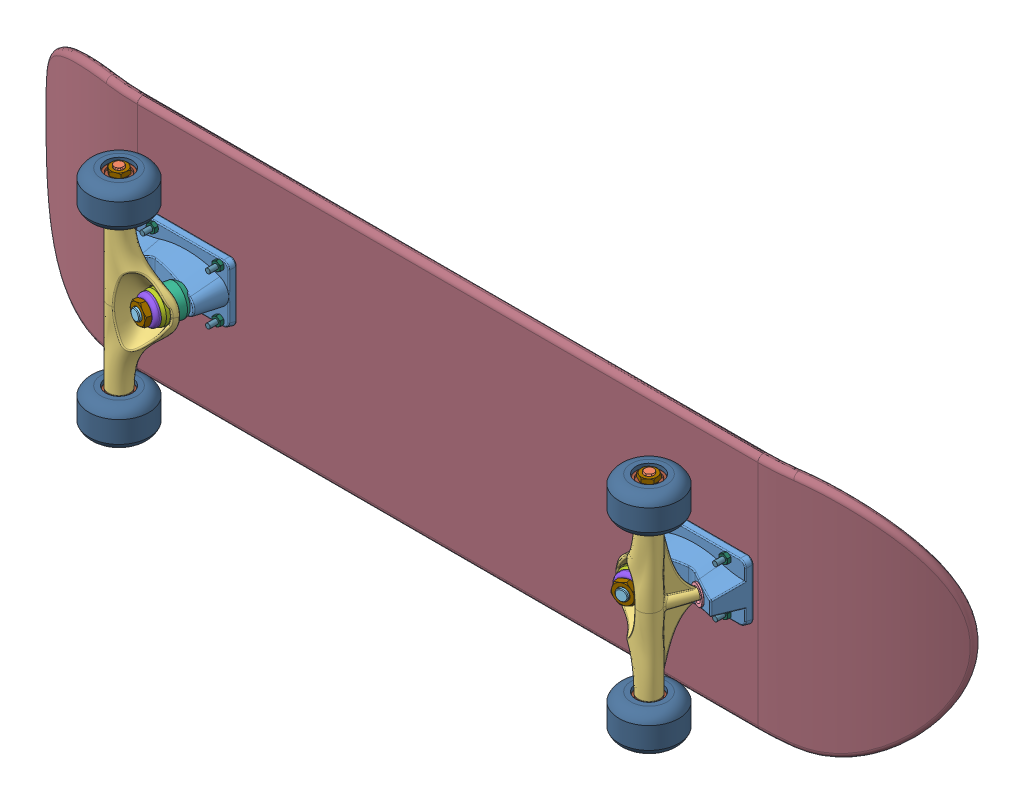
SolidWorks assembly Assembly - Skate Board, configuration Default. Lengths in mm.
Overall size (788.92 215.39 157.78).
61 component instances, 15 part files, 19 mates.
Components (placement in the parent):
- Assem1-1: Assem1 [Default] at (-144.7404 14.9244 -85.2908) x (0.992671 0 0.120847) z (-0.120847 0 0.992671) size (83.68 196.33 93.83)
  - wheels plate-1: wheels plate [Default] at (-66.8998 0 44.2716) x (0.992671 0 -0.120847) z (0.120847 0 0.992671) size (79.62 49.62 33.33)
  - axle-1: axle [Default] at (-65.9942 0 97.9359) x (-0.180982 0 0.983486) z (0 -1 0) size (9.24 8.23 196.33)
  - mainaxle-1: mainaxle [Default] at (-65.9942 0 97.9359) x (-0.95874 0 0.284283) z (0 1 0) size (51.62 57.48 130)
  - pivot-1: pivot [Default] at (-82.5284 0 71.0438) x (0.197568 0.974284 -0.108339) z (-0.854272 0.225323 0.468454) size (16 11.5 16)
  - pin-1: pin [Default] at (-47.2125 0 100.8054) x (0.921951 0.377058 0.088514) z (-0.375332 0.92619 -0.036035) size (13.5 45 13.5)
  - rubber brush 1-1: rubber brush 1 [Default] at (-44.054 0 67.9067) x (-0.944411 0.316016 -0.09067) z (0.31457 0.948754 0.030201) size (25.1 13.5 25.1)
  - rubber brush 2-1: rubber brush 2 [Default] at (-45.0814 0 78.6075) x (-0.637434 -0.768071 -0.061198) z (-0.764555 0.640365 -0.073403) size (24.92 14.75 24.92)
  - washer 1-1: washer 1 [Default] at (-46.1183 0 89.4078) x (-0.982393 0.161268 -0.094317) z (0.16053 0.986911 0.015412) size (23 4.5 23)
  - hex thin nut chamfered gradeab_iso-2: hex thin nut chamfered gradeab_iso [Hexagon Thin Nut ISO - 4035 - M10 - N] at (-47.0262 0 98.8643) x (-0.963954 0.249456 -0.092546) z (-0.095568 0 0.995423) size (16 18.48 5)
  - wheel full-1: wheel full [Default] at (-53.9934 -77.2719 56.6368) x (0.712103 0 -0.702075) z (0.702075 0 0.712103) size (50 32 50)
    - wheel-1: wheel [Default] at (-37.5409 -1.7281 20.9838) size (50 32 50)
    - wheel 2-1: wheel 2 [Default] at (-37.5409 7.7719 20.9838) x (0.941189 0 0.337879) z (-0.337879 0 0.941189) size (22 7 22)
    - wheel 2-2: wheel 2 [Default] at (-37.5409 -11.2281 20.9838) x (0.993508 0 -0.11376) z (0.11376 0 0.993508) size (22 7 22)
  - washer 2-2: washer 2 [Default] at (-65.9942 66 97.9359) x (1 0 0) z (0 -1 0) size (11 11 1)
  - washer 2-3: washer 2 [Default] at (-65.9942 -66 97.9359) x (1 0 0) z (0 1 0) size (11 11 1)
  - wheel full-2: wheel full [Default] at (-30.942 80.7281 122.8555) x (0.428722 0 0.903436) z (-0.903436 0 0.428722) size (50 32 50)
    - wheel-1: wheel [Default] at (-37.5409 -1.7281 20.9838) size (50 32 50)
    - wheel 2-1: wheel 2 [Default] at (-37.5409 7.7719 20.9838) x (0.941189 0 0.337879) z (-0.337879 0 0.941189) size (22 7 22)
    - wheel 2-2: wheel 2 [Default] at (-37.5409 -11.2281 20.9838) x (0.993508 0 -0.11376) z (0.11376 0 0.993508) size (22 7 22)
  - hex thin nut chamfered gradeab_iso-6: hex thin nut chamfered gradeab_iso [Hexagon Thin Nut ISO - 4035 - M8 - N] at (-65.9942 -96 97.9359) x (1 0 0) z (0 -1 0) size (13 15.01 4)
  - hex thin nut chamfered gradeab_iso-7: hex thin nut chamfered gradeab_iso [Hexagon Thin Nut ISO - 4035 - M8 - N] at (-65.9942 96 97.9359) x (0.999993 0 0.003741) z (0 1 0) size (13 15.01 4)
- board-1: board [Default] at (0 14.9244 -53.9283) x (1 0 0) z (0 1 0) size (788.92 69.73 215.39)
- Assem1-4: Assem1 [Default] at (144.7404 14.9244 -85.2908) x (-0.992671 0 0.120847) z (0.120847 0 0.992671) size (83.68 196.33 93.83)
  - wheels plate-1: wheels plate [Default] at (-66.8998 0 44.2716) x (0.992671 0 -0.120847) z (0.120847 0 0.992671) size (79.62 49.62 33.33)
  - axle-1: axle [Default] at (-65.9942 0 97.9359) x (-0.180982 0 0.983486) z (0 -1 0) size (9.24 8.23 196.33)
  - mainaxle-1: mainaxle [Default] at (-65.9942 0 97.9359) x (-0.95874 0 0.284283) z (0 1 0) size (51.62 57.48 130)
  - pivot-1: pivot [Default] at (-82.5284 0 71.0438) x (0.197568 0.974284 -0.108339) z (-0.854272 0.225323 0.468454) size (16 11.5 16)
  - pin-1: pin [Default] at (-47.2125 0 100.8054) x (0.921951 0.377058 0.088514) z (-0.375332 0.92619 -0.036035) size (13.5 45 13.5)
  - rubber brush 1-1: rubber brush 1 [Default] at (-44.054 0 67.9067) x (-0.944411 0.316016 -0.09067) z (0.31457 0.948754 0.030201) size (25.1 13.5 25.1)
  - rubber brush 2-1: rubber brush 2 [Default] at (-45.0814 0 78.6075) x (-0.637434 -0.768071 -0.061198) z (-0.764555 0.640365 -0.073403) size (24.92 14.75 24.92)
  - washer 1-1: washer 1 [Default] at (-46.1183 0 89.4078) x (-0.982393 0.161268 -0.094317) z (0.16053 0.986911 0.015412) size (23 4.5 23)
  - hex thin nut chamfered gradeab_iso-2: hex thin nut chamfered gradeab_iso [Hexagon Thin Nut ISO - 4035 - M10 - N] at (-47.0262 0 98.8643) x (-0.963954 0.249456 -0.092546) z (-0.095568 0 0.995423) size (16 18.48 5)
  - wheel full-1: wheel full [Default] at (-53.9934 -77.2719 56.6368) x (0.712103 0 -0.702075) z (0.702075 0 0.712103) size (50 32 50)
    - wheel-1: wheel [Default] at (-37.5409 -1.7281 20.9838) size (50 32 50)
    - wheel 2-1: wheel 2 [Default] at (-37.5409 7.7719 20.9838) x (0.941189 0 0.337879) z (-0.337879 0 0.941189) size (22 7 22)
    - wheel 2-2: wheel 2 [Default] at (-37.5409 -11.2281 20.9838) x (0.993508 0 -0.11376) z (0.11376 0 0.993508) size (22 7 22)
  - washer 2-2: washer 2 [Default] at (-65.9942 66 97.9359) x (1 0 0) z (0 -1 0) size (11 11 1)
  - washer 2-3: washer 2 [Default] at (-65.9942 -66 97.9359) x (1 0 0) z (0 1 0) size (11 11 1)
  - wheel full-2: wheel full [Default] at (-30.942 80.7281 122.8555) x (0.428722 0 0.903436) z (-0.903436 0 0.428722) size (50 32 50)
    - wheel-1: wheel [Default] at (-37.5409 -1.7281 20.9838) size (50 32 50)
    - wheel 2-1: wheel 2 [Default] at (-37.5409 7.7719 20.9838) x (0.941189 0 0.337879) z (-0.337879 0 0.941189) size (22 7 22)
    - wheel 2-2: wheel 2 [Default] at (-37.5409 -11.2281 20.9838) x (0.993508 0 -0.11376) z (0.11376 0 0.993508) size (22 7 22)
  - hex thin nut chamfered gradeab_iso-6: hex thin nut chamfered gradeab_iso [Hexagon Thin Nut ISO - 4035 - M8 - N] at (-65.9942 -96 97.9359) x (1 0 0) z (0 -1 0) size (13 15.01 4)
  - hex thin nut chamfered gradeab_iso-7: hex thin nut chamfered gradeab_iso [Hexagon Thin Nut ISO - 4035 - M8 - N] at (-65.9942 96 97.9359) x (0.999993 0 0.003741) z (0 1 0) size (13 15.01 4)
- flat head screw_am-161: flat head screw_am [B18.6.7M - M4 x 0.7 x 25 Type I Cross Recessed FHMS --25N] at (185 -5.0756 -58.4283) x (0 0 1) z (-1 0 0) size (25 8.4 8.4)
- flat head screw_am-162: flat head screw_am [B18.6.7M - M4 x 0.7 x 25 Type I Cross Recessed FHMS --25N] at (240 -5.0756 -58.4283) x (0 0 1) z (-1 0 0) size (25 8.4 8.4)
- flat head screw_am-163: flat head screw_am [B18.6.7M - M4 x 0.7 x 25 Type I Cross Recessed FHMS --25N] at (185 34.9244 -58.4283) x (0 0 1) z (-1 0 0) size (25 8.4 8.4)
- flat head screw_am-164: flat head screw_am [B18.6.7M - M4 x 0.7 x 25 Type I Cross Recessed FHMS --25N] at (240 34.9244 -58.4283) x (0 0 1) z (-1 0 0) size (25 8.4 8.4)
- flat head screw_am-165: flat head screw_am [B18.6.7M - M4 x 0.7 x 25 Type I Cross Recessed FHMS --25N] at (-185 -5.0756 -58.4283) x (0 0 1) z (-1 0 0) size (25 8.4 8.4)
- flat head screw_am-166: flat head screw_am [B18.6.7M - M4 x 0.7 x 25 Type I Cross Recessed FHMS --25N] at (-240 -5.0756 -58.4283) x (0 0 1) z (-1 0 0) size (25 8.4 8.4)
- flat head screw_am-167: flat head screw_am [B18.6.7M - M4 x 0.7 x 25 Type I Cross Recessed FHMS --25N] at (-185 34.9244 -58.4283) x (0 0 1) z (-1 0 0) size (25 8.4 8.4)
- flat head screw_am-168: flat head screw_am [B18.6.7M - M4 x 0.7 x 25 Type I Cross Recessed FHMS --25N] at (-240 34.9244 -58.4283) x (0 0 1) z (-1 0 0) size (25 8.4 8.4)
- hex nut style 1_am-81: hex nut style 1_am [B18.2.4.1M - Hex nut, Style 1,  M4 x 0.7 --D-N] at (185 -5.0756 -40.2283) size (7 8.08 3.2)
- hex nut style 1_am-82: hex nut style 1_am [B18.2.4.1M - Hex nut, Style 1,  M4 x 0.7 --D-N] at (240 -5.0756 -40.2283) size (7 8.08 3.2)
- hex nut style 1_am-83: hex nut style 1_am [B18.2.4.1M - Hex nut, Style 1,  M4 x 0.7 --D-N] at (185 34.9244 -40.2283) size (7 8.08 3.2)
- hex nut style 1_am-84: hex nut style 1_am [B18.2.4.1M - Hex nut, Style 1,  M4 x 0.7 --D-N] at (240 34.9244 -40.2283) size (7 8.08 3.2)
- hex nut style 1_am-85: hex nut style 1_am [B18.2.4.1M - Hex nut, Style 1,  M4 x 0.7 --D-N] at (-185 -5.0756 -43.4283) x (-1 0 0) z (0 0 -1) size (7 8.08 3.2)
- hex nut style 1_am-86: hex nut style 1_am [B18.2.4.1M - Hex nut, Style 1,  M4 x 0.7 --D-N] at (-240 -5.0756 -43.4283) x (-1 0 0) z (0 0 -1) size (7 8.08 3.2)
- hex nut style 1_am-87: hex nut style 1_am [B18.2.4.1M - Hex nut, Style 1,  M4 x 0.7 --D-N] at (-185 34.9244 -43.4283) x (-1 0 0) z (0 0 -1) size (7 8.08 3.2)
- hex nut style 1_am-88: hex nut style 1_am [B18.2.4.1M - Hex nut, Style 1,  M4 x 0.7 --D-N] at (-240 34.9244 -43.4283) x (-1 0 0) z (0 0 -1) size (7 8.08 3.2)
Mates (geometry in assembly coordinates):
- Concentric1: concentric anti-aligned: cylinder of Assem1-1/wheels plate-1 through (-240 -5.0756 -43.4283) axis (0 0 1) radius 2; cylinder of board-1 through (-240 -5.0756 -58.4283) axis (0 0 -1) radius 2.25
- Concentric2: concentric anti-aligned: cylinder of Assem1-1/wheels plate-1 through (-185 34.9244 -43.4283) axis (0 0 1) radius 2; cylinder of board-1 through (-185 34.9244 -58.4283) axis (0 0 -1) radius 2.25
- Coincident1: coincident anti-aligned: plane of Assem1-1/wheels plate-1 through (-216.5 14.9244 -49.4283) normal (0 0 -1); plane of board-1 through (-260 -87.5756 -49.4283) normal (0 0 1)
- Concentric3: concentric anti-aligned: cylinder of board-1 through (185 -5.0756 -58.4283) axis (0 0 -1) radius 2.25; cylinder of Assem1-4/wheels plate-1 through (185 -5.0756 -43.4283) axis (0 0 1) radius 2
- Concentric4: concentric anti-aligned: cylinder of board-1 through (240 34.9244 -58.4283) axis (0 0 -1) radius 2.25; cylinder of Assem1-4/wheels plate-1 through (240 34.9244 -43.4283) axis (0 0 1) radius 2
- Coincident2: coincident anti-aligned: plane of board-1 through (-260 -87.5756 -49.4283) normal (0 0 1); plane of Assem1-4/wheels plate-1 through (216.5 14.9244 -49.4283) normal (0 0 -1)
- Coincident47: coincident aligned: plane of board-1 through (0 14.9244 -53.9283) normal (1 0 0); plane of assembly through (0 0 0) normal (1 0 0)
- Coincident185: coincident aligned: cone of board-1 through (185 -5.0756 -58.4283) axis (0 0 1); cone of flat head screw_am-161 through (185 -5.0756 -57.9283) axis (0 0 1)
- Coincident186: coincident aligned: cone of board-1 through (240 -5.0756 -58.4283) axis (0 0 1); cone of flat head screw_am-162 through (240 -5.0756 -57.9283) axis (0 0 1)
- Coincident187: coincident aligned: cone of board-1 through (185 34.9244 -58.4283) axis (0 0 1); cone of flat head screw_am-163 through (185 34.9244 -57.9283) axis (0 0 1)
- Coincident188: coincident aligned: cone of board-1 through (240 34.9244 -58.4283) axis (0 0 1); cone of flat head screw_am-164 through (240 34.9244 -57.9283) axis (0 0 1)
- Concentric110: concentric anti-aligned: cylinder of flat head screw_am-161 through (185 -5.0756 -64.7783) axis (0 0 -1) radius 2; cylinder of hex nut style 1_am-81 through (185 -5.0756 -65.2658) axis (0 0 1) radius 2
- Coincident189: coincident anti-aligned: plane of Assem1-4/wheels plate-1 through (216.5 14.9244 -43.4283) normal (0 0 1); plane of hex nut style 1_am-81 through (185 -1.0342 -43.4283) normal (0 0 -1)
- Concentric111: concentric anti-aligned: cylinder of flat head screw_am-162 through (240 -5.0756 -64.7783) axis (0 0 -1) radius 2; cylinder of hex nut style 1_am-82 through (240 -5.0756 -65.2658) axis (0 0 1) radius 2
- Coincident190: coincident anti-aligned: plane of Assem1-4/wheels plate-1 through (216.5 14.9244 -43.4283) normal (0 0 1); plane of hex nut style 1_am-82 through (240 -1.0342 -43.4283) normal (0 0 -1)
- Concentric112: concentric anti-aligned: cylinder of flat head screw_am-163 through (185 34.9244 -64.7783) axis (0 0 -1) radius 2; cylinder of hex nut style 1_am-83 through (185 34.9244 -65.2658) axis (0 0 1) radius 2
- Coincident191: coincident anti-aligned: plane of Assem1-4/wheels plate-1 through (216.5 14.9244 -43.4283) normal (0 0 1); plane of hex nut style 1_am-83 through (185 38.9658 -43.4283) normal (0 0 -1)
- Concentric113: concentric anti-aligned: cylinder of flat head screw_am-164 through (240 34.9244 -64.7783) axis (0 0 -1) radius 2; cylinder of hex nut style 1_am-84 through (240 34.9244 -65.2658) axis (0 0 1) radius 2
- Coincident192: coincident anti-aligned: plane of Assem1-4/wheels plate-1 through (216.5 14.9244 -43.4283) normal (0 0 1); plane of hex nut style 1_am-84 through (240 38.9658 -43.4283) normal (0 0 -1)
